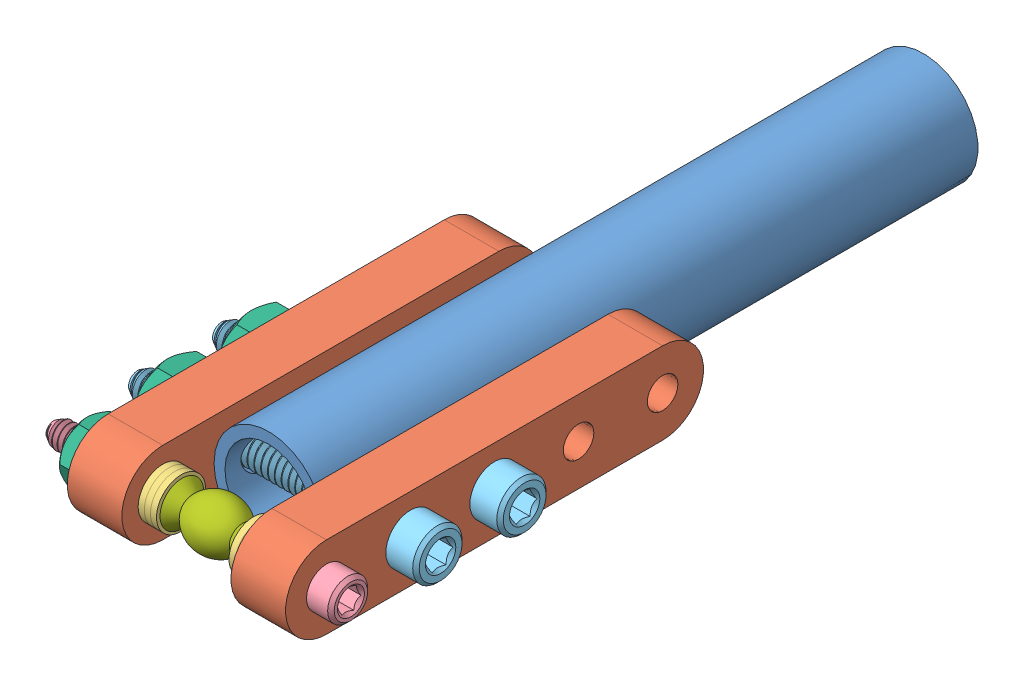
SolidWorks assembly Diff Pivot Bottom, configuration Default. Lengths in mm.
Overall size (35.29 12.7 86.93).
16 component instances, 7 part files, 32 mates.
Components (placement in the parent):
- 3 inch Aluminum Rod-1: 3 inch Aluminum Rod [Default] at (25.2275 39.993 -257.4677) size (12.7 12.7 76.2)
- 5 Hole Aluminum Beam-1: 5 Hole Aluminum Beam [Default] at (37.9275 39.993 84.5433) x (0 0 -1) z (0 1 0) size (48.64 6.35 9.53)
- 5 Hole Aluminum Beam-2: 5 Hole Aluminum Beam [Default] at (18.8775 39.993 84.5433) x (0 0 -1) z (0 1 0) size (48.64 6.35 9.53)
- 4-40 Washer-1: 4-40 Washer [Default] at (18.8775 39.993 104.1013) x (0 -1 0) z (0 0 1) size (5.71 0.71 5.71)
- 4-40 Washer-2: 4-40 Washer [Default] at (19.5887 39.993 104.1013) x (0 -1 0) z (0 0 1) size (5.71 0.71 5.71)
- 4-40 Washer-3: 4-40 Washer [Default] at (20.2999 39.993 104.1013) x (0 -1 0) z (0 0 1) size (5.71 0.71 5.71)
- 4-40 Washer-4: 4-40 Washer [Default] at (29.4439 39.993 104.1013) x (0 -1 0) z (0 0 1) size (5.71 0.71 5.71)
- 4-40 Washer-5: 4-40 Washer [Default] at (30.1551 39.993 104.1013) x (0 -1 0) z (0 0 1) size (5.71 0.71 5.71)
- 4-40 Washer-6: 4-40 Washer [Default] at (30.8663 39.993 104.1013) x (0 -1 0) z (0 0 1) size (5.71 0.71 5.71)
- 4-40_SHCS-1: 4-40_SHCS [4-40 SHCS X 1.250] at (6.1775 39.993 104.1013) x (0 0.924225 0.381849) z (1 0 0) size (4.65 4.65 34.63)
- 6-32_SHCS-1: 6-32_SHCS [6-32 SHCS X 1.250] at (6.1775 39.993 94.3223) x (0 0 -1) z (1 0 0) size (5.74 5.74 35.26)
- 6-32_SHCS-2: 6-32_SHCS [6-32 SHCS X 1.250] at (6.1775 39.993 84.5433) x (0 0 -1) z (1 0 0) size (5.74 5.74 35.26)
- hex_nut-2: hex_nut [#4-40] at (12.5275 39.993 104.1013) x (0 0.381849 -0.924225) z (0 0.924225 0.381849) size (6.35 2.49 8.06)
- hex_nut-3: hex_nut [#6-32] at (12.5275 39.993 94.3223) x (0 0.381849 -0.924225) z (0 0.924225 0.381849) size (7.92 2.9 10.06)
- hex_nut-4: hex_nut [#6-32] at (12.5275 39.993 84.5433) x (0 1 0) z (0 0 1) size (7.92 2.9 10.06)
- Ball bearing-1: Ball bearing [Default] at (21.1 39.993 104.1013) x (0 -1 0) z (0 0 1) size (5.73 8.26 5.73)
Mates (geometry in assembly coordinates):
- Concentric1: concentric anti-aligned: cylinder of 3 inch Aluminum Rod-1 through (-152.5725 39.993 84.5433) axis (1 0 0) radius 1.9558; cylinder of 5 Hole Aluminum Beam-2 through (12.5275 39.993 84.5433) axis (-1 0 0) radius 1.778
- Concentric2: concentric anti-aligned: cylinder of 3 inch Aluminum Rod-1 through (-152.5725 39.993 84.5433) axis (1 0 0) radius 1.9558; cylinder of 5 Hole Aluminum Beam-1 through (31.5775 39.993 84.5433) axis (-1 0 0) radius 1.778
- Concentric3: concentric aligned: cylinder of 5 Hole Aluminum Beam-2 through (12.5275 39.993 94.3223) axis (-1 0 0) radius 1.778; cylinder of 5 Hole Aluminum Beam-1 through (31.5775 39.993 94.3223) axis (-1 0 0) radius 1.778
- Concentric4: concentric anti-aligned: cylinder of 5 Hole Aluminum Beam-2 through (12.5275 39.993 94.3223) axis (-1 0 0) radius 1.778; cylinder of 3 inch Aluminum Rod-1 through (-152.5725 39.993 94.3223) axis (1 0 0) radius 1.9558
- Concentric5: concentric anti-aligned: cylinder of 3 inch Aluminum Rod-1 through (-152.5725 39.993 84.5433) axis (1 0 0) radius 1.9558; cylinder of hex_nut-4 through (12.4514 39.993 84.5433) axis (-1 0 0) radius 1.323
- Concentric7: concentric anti-aligned: cylinder of 3 inch Aluminum Rod-1 through (-152.5725 39.993 84.5433) axis (1 0 0) radius 1.9558; cylinder of 6-32_SHCS-2 through (50.6275 39.993 84.5433) axis (-1 0 0) radius 2.8702
- Concentric8: concentric anti-aligned: cylinder of 6-32_SHCS-1 through (50.6275 39.993 94.3223) axis (-1 0 0) radius 2.8702; cylinder of 3 inch Aluminum Rod-1 through (-152.5725 39.993 94.3223) axis (1 0 0) radius 1.9558
- Concentric9: concentric aligned: cylinder of 6-32_SHCS-1 through (50.6275 39.993 94.3223) axis (-1 0 0) radius 2.8702; cylinder of hex_nut-3 through (12.4514 39.993 94.3223) axis (-1 0 0) radius 1.323
- Concentric10: concentric anti-aligned: cylinder of 5 Hole Aluminum Beam-1 through (31.5775 39.993 104.1013) axis (-1 0 0) radius 1.778; cylinder of 4-40 Washer-5 through (30.8663 39.993 104.1013) axis (1 0 0) radius 1.4732
- Concentric11: concentric anti-aligned: cylinder of 5 Hole Aluminum Beam-1 through (31.5775 39.993 104.1013) axis (-1 0 0) radius 1.778; cylinder of 4-40 Washer-6 through (31.5775 39.993 104.1013) axis (1 0 0) radius 1.4732
- Concentric12: concentric anti-aligned: cylinder of 5 Hole Aluminum Beam-1 through (31.5775 39.993 104.1013) axis (-1 0 0) radius 1.778; cylinder of 4-40 Washer-4 through (30.1551 39.993 104.1013) axis (1 0 0) radius 1.4732
- Concentric13: concentric anti-aligned: cylinder of 5 Hole Aluminum Beam-1 through (31.5775 39.993 104.1013) axis (-1 0 0) radius 1.778; cylinder of 4-40 Washer-3 through (21.0111 39.993 104.1013) axis (1 0 0) radius 1.4732
- Concentric14: concentric anti-aligned: cylinder of 5 Hole Aluminum Beam-1 through (31.5775 39.993 104.1013) axis (-1 0 0) radius 1.778; cylinder of 4-40 Washer-2 through (20.2999 39.993 104.1013) axis (1 0 0) radius 1.4732
- Concentric15: concentric anti-aligned: cylinder of 5 Hole Aluminum Beam-1 through (31.5775 39.993 104.1013) axis (-1 0 0) radius 1.778; cylinder of 4-40 Washer-1 through (19.5887 39.993 104.1013) axis (1 0 0) radius 1.4732
- Concentric16: concentric aligned: cylinder of 5 Hole Aluminum Beam-1 through (31.5775 39.993 104.1013) axis (-1 0 0) radius 1.778; cylinder of 4-40_SHCS-1 through (50.6275 39.993 104.1013) axis (-1 0 0) radius 2.3241
- Concentric17: concentric aligned: cylinder of 5 Hole Aluminum Beam-1 through (31.5775 39.993 104.1013) axis (-1 0 0) radius 1.778; cylinder of hex_nut-2 through (12.1339 39.993 104.1013) axis (-1 0 0) radius 1.0787
- Tangent1: tangent anti-aligned: cylinder of 3 inch Aluminum Rod-1 through (25.2275 39.993 98.1323) axis (0 0 -1) radius 6.35; plane of 5 Hole Aluminum Beam-1 through (31.5775 39.993 104.1013) normal (-1 0 0)
- Tangent2: tangent anti-aligned: cylinder of 3 inch Aluminum Rod-1 through (25.2275 39.993 98.1323) axis (0 0 -1) radius 6.35; plane of 5 Hole Aluminum Beam-2 through (18.8775 39.993 104.1013) normal (1 0 0)
- Coincident1: coincident anti-aligned: plane of 5 Hole Aluminum Beam-1 through (37.9275 39.993 104.1013) normal (1 0 0); plane of 6-32_SHCS-1 through (37.9275 39.993 94.3223) normal (-1 0 0)
- Coincident2: coincident anti-aligned: plane of 5 Hole Aluminum Beam-1 through (37.9275 39.993 104.1013) normal (1 0 0); plane of 6-32_SHCS-2 through (37.9275 39.993 84.5433) normal (-1 0 0)
- Coincident3: coincident anti-aligned: plane of 5 Hole Aluminum Beam-1 through (37.9275 39.993 104.1013) normal (1 0 0); plane of 4-40_SHCS-1 through (37.9275 39.993 104.1013) normal (-1 0 0)
- Coincident4: coincident anti-aligned: plane of 5 Hole Aluminum Beam-2 through (12.5275 39.993 104.1013) normal (-1 0 0); plane of hex_nut-3 through (12.5275 32.137 95.3638) normal (1 0 0)
- Coincident5: coincident anti-aligned: plane of 5 Hole Aluminum Beam-2 through (12.5275 39.993 104.1013) normal (-1 0 0); plane of hex_nut-2 through (12.5275 36.6047 102.7014) normal (1 0 0)
- Coincident6: coincident anti-aligned: plane of 5 Hole Aluminum Beam-2 through (12.5275 39.993 104.1013) normal (-1 0 0); plane of hex_nut-4 through (12.5275 36.0306 77.6803) normal (1 0 0)
- Coincident7: coincident anti-aligned: plane of 4-40 Washer-5 through (30.8663 39.993 104.1013) normal (1 0 0); plane of 4-40 Washer-6 through (30.8663 39.993 104.1013) normal (-1 0 0)
- Coincident8: coincident anti-aligned: plane of 4-40 Washer-4 through (30.1551 39.993 104.1013) normal (1 0 0); plane of 4-40 Washer-5 through (30.1551 39.993 104.1013) normal (-1 0 0)
- Coincident9: coincident anti-aligned: plane of 4-40 Washer-2 through (20.2999 39.993 104.1013) normal (1 0 0); plane of 4-40 Washer-3 through (20.2999 39.993 104.1013) normal (-1 0 0)
- Coincident10: coincident anti-aligned: plane of 4-40 Washer-1 through (19.5887 39.993 104.1013) normal (1 0 0); plane of 4-40 Washer-2 through (19.5887 39.993 104.1013) normal (-1 0 0)
- Coincident11: coincident anti-aligned: plane of 5 Hole Aluminum Beam-1 through (31.5775 39.993 104.1013) normal (-1 0 0); plane of 4-40 Washer-6 through (31.5775 39.993 104.1013) normal (1 0 0)
- Coincident12: coincident anti-aligned: plane of 5 Hole Aluminum Beam-2 through (18.8775 39.993 104.1013) normal (1 0 0); plane of 4-40 Washer-1 through (18.8775 39.993 104.1013) normal (-1 0 0)
- Coincident13: coincident anti-aligned: plane of Ball bearing-1; plane of assembly through (25.2275 0 0) normal (-1 0 0)
- Concentric18: concentric anti-aligned: cylinder of 4-40_SHCS-1 through (50.6275 39.993 104.1013) axis (-1 0 0) radius 2.3241; cylinder of Ball bearing-1 through (29.101 39.993 104.1013) axis (1 0 0) radius 1.016
